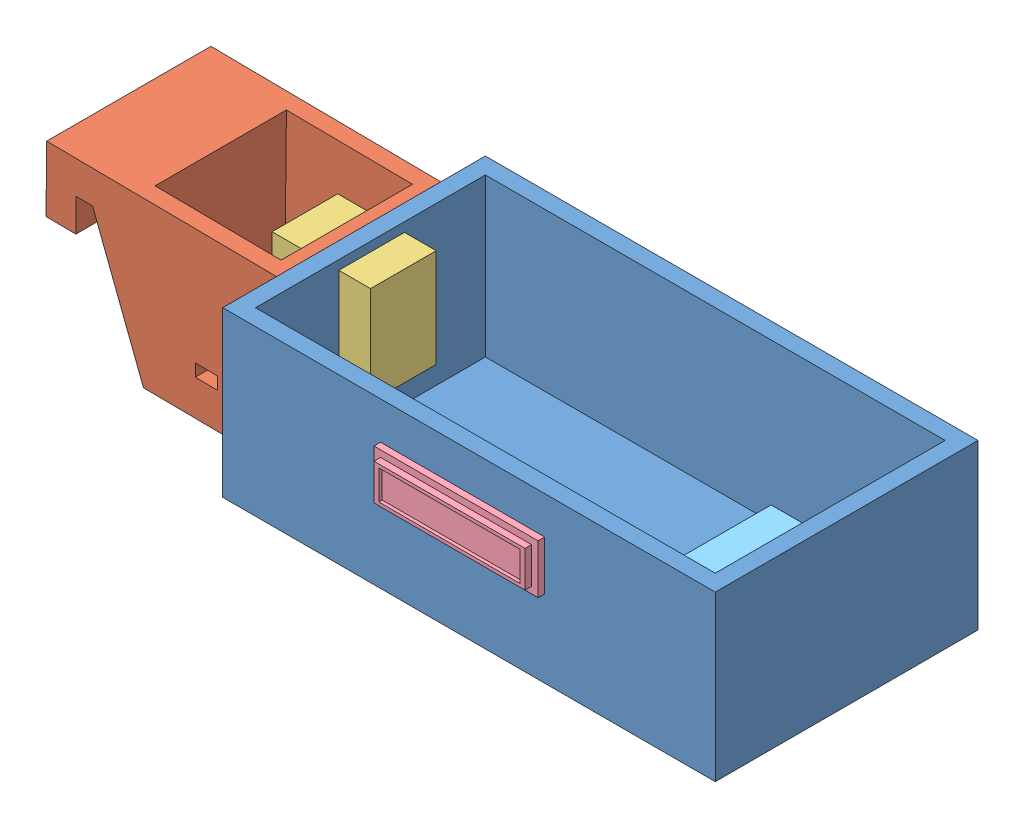
SolidWorks assembly Assem1, configuration Default. Lengths in mm.
Overall size (220.52 50.74 84).
5 component instances, 5 part files, 2 mates.
Components (placement in the parent):
- Part2-1: Part2 [Default] at (57.8482 61.715 80.6399) x (1 0 0) z (0 1 0) size (150 80 50)
- Part1-1: Part1 [Default] at (-77.3489 80.4879 134.1088) x (-0.999944 0.010541 0) z (0 0 -1) size (70 50 50)
- Part6-5: Part6 [Default] at (3.5521 111.2153 121.0193) x (0 1 0) z (-1 0 0) size (30 20 32.5)
- Part7-1: Part7 [Default] at (48.024 89.2832 150.5134) x (0 0 1) z (1 0 0) size (4 15 50)
- Part8-1: Part8 [Default] at (90.7056 68.715 105.2358) x (0 0 -1) z (1 0 0) size (50 10 35)
Mates (geometry in assembly coordinates):
- Coincident1: coincident aligned: line of Part2-1 through (-21.1075 111.715 70.5134) axis (0 0 1); line of Part1-1 through (-21.1075 111.715 84.1088) axis (0 0 1)
- Coincident2: coincident: plane of Part2-1 through (-21.1075 111.715 150.5134) normal (0 0 1); line of Part7-1 through (76.9473 100.2686 150.5134) axis (-1 0 0)
